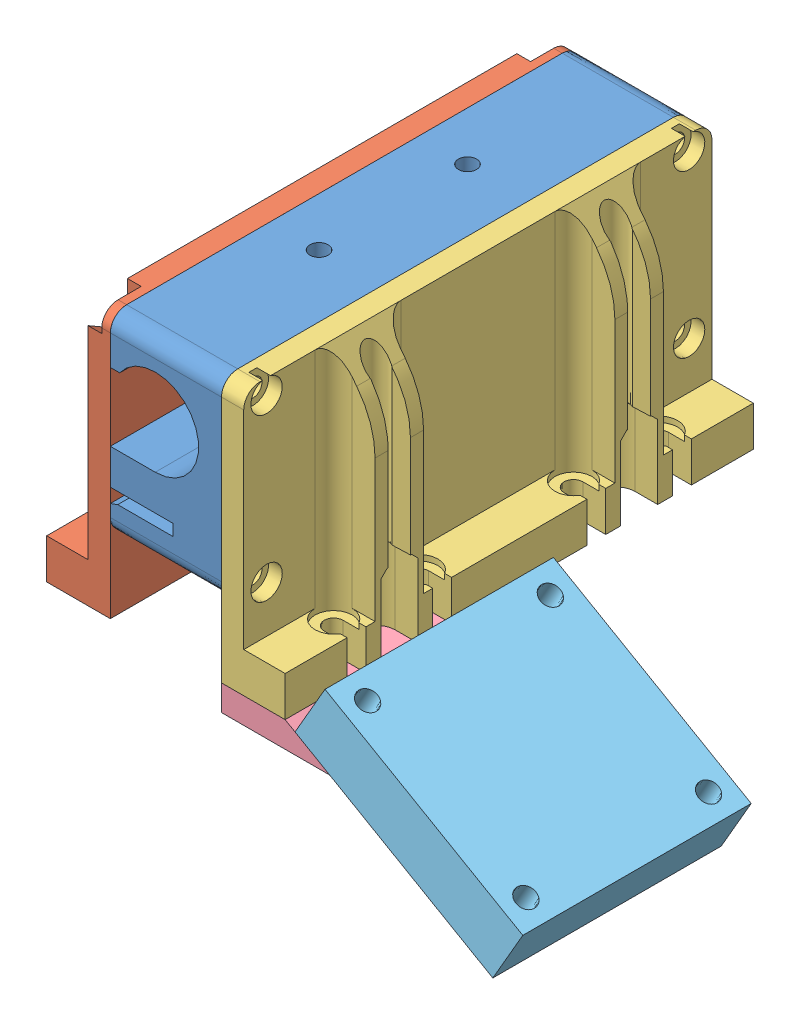
SolidWorks assembly Assem1, configuration Default. Lengths in mm.
Overall size (83.39 76.39 82).
6 component instances, 6 part files, 16 mates.
Components (placement in the parent):
- x-carriage-1: x-carriage [Default] at (14.0206 65.7443 26.0394) size (19.46 60 82)
- nozzle-mount-front-1: nozzle-mount-front [Default] at (-4.994 66.5947 108.0394) x (0 0 -1) z (1 0 0) size (82 46.39 11.15)
- nozzle-mount-rear-1: nozzle-mount-rear [Default] at (36.7706 66.5947 26.0394) x (0 0 1) z (-1 0 0) size (82 46.39 11.15)
- Part2^Assem1-1: Part2^Assem1 [Default] at (-4.994 31.9947 108.0394) x (0 0 1) z (0 -1 0) (virtual)
- Fan Holder-1: Fan Holder [Default] at (36.7706 31.9947 26.0394) x (0 0 -1) z (0 -1 0) size (40 19.86 5.84)
- Fan-1: Fan [Default] at (55.8232 20.9947 88.0394) x (0.866025 -0.5 0) z (0 0 1) size (40 10.5 40)
Mates (geometry in assembly coordinates):
- Concentric1: concentric anti-aligned: cylinder of x-carriage-1 through (25.6206 47.1943 104.0394) axis (-1 0 0) radius 1.7; circle of nozzle-mount-front-1
- Concentric2: concentric anti-aligned: cylinder of x-carriage-1 through (25.6206 47.1943 30.0394) axis (-1 0 0) radius 1.7; cylinder of nozzle-mount-front-1 through (-4.994 47.1943 30.0394) axis (1 0 0) radius 1.6
- Coincident1: coincident anti-aligned: plane of x-carriage-1 through (6.156 65.7443 26.0394) normal (-1 0 0); plane of nozzle-mount-front-1 through (6.156 75.3447 28.8894) normal (1 0 0)
- Concentric3: concentric anti-aligned: cylinder of x-carriage-1 through (25.6206 75.5343 104.0394) axis (-1 0 0) radius 1.7; cylinder of nozzle-mount-rear-1 through (27.1206 75.5343 104.0394) axis (1 0 0) radius 2.75
- Coincident2: coincident anti-aligned: plane of x-carriage-1 through (25.6206 16.1943 108.0394) normal (1 0 0); plane of nozzle-mount-rear-1 through (25.6206 75.3447 105.1894) normal (-1 0 0)
- Coincident3: coincident aligned: plane of nozzle-mount-front-1 through (6.156 78.1947 28.8894) normal (0 1 0); plane of nozzle-mount-rear-1 through (25.6206 78.1947 105.1894) normal (0 1 0)
- InPlace1: in place: plane of nozzle-mount-front-1 through (3.006 31.9947 26.0394) normal (0 -1 0); plane of ? through (0 31.9947 0) normal (0 -1 0); moOrthogonalPlaneRef_w of nozzle-mount-front-1 through (3.006 31.9947 26.0394) normal (0 -1 0); unknown of ?; plane of nozzle-mount-front-1 through (3.006 31.9947 26.0394) normal (0 -1 0); unknown of ?; plane of nozzle-mount-front-1 through (3.006 31.9947 26.0394) normal (0 -1 0); unknown of Part2^Assem1-1
- Coincident4: coincident aligned: plane of nozzle-mount-front-1; plane of Part2^Assem1-1
- Coincident5: coincident aligned: moOrthogonalPlaneRef_w of nozzle-mount-front-1 through (-4.994 31.9947 108.0394) normal (-1 0 0); plane of Part2^Assem1-1
- Coincident6: coincident anti-aligned: moOrthogonalPlaneRef_w of nozzle-mount-front-1 through (-4.994 31.9947 108.0394) normal (0 0 -1); plane of Part2^Assem1-1
- InPlace2: in place: plane of nozzle-mount-rear-1 through (28.7706 31.9947 108.0394) normal (0 -1 0); plane of ? through (0 31.9947 0) normal (0 -1 0); plane of nozzle-mount-rear-1 through (28.7706 31.9947 108.0394) normal (0 -1 0); unknown of ?; plane of nozzle-mount-rear-1 through (28.7706 31.9947 108.0394) normal (0 -1 0); line of ? through (-55 0 31.9947) axis (0 -1 0); plane of nozzle-mount-rear-1 through (28.7706 31.9947 108.0394) normal (0 -1 0); unknown of Fan Holder-1
- Coincident7: coincident aligned: plane of nozzle-mount-rear-1; plane of Fan Holder-1
- Coincident8: coincident aligned: moOrthogonalPlaneRef_w of nozzle-mount-rear-1 through (36.7706 31.9947 26.0394) normal (1 0 0); plane of Fan Holder-1
- Coincident9: coincident anti-aligned: moOrthogonalPlaneRef_w of nozzle-mount-rear-1 through (36.7706 31.9947 26.0394) normal (0 0 1); plane of Fan Holder-1
- Coincident10: coincident anti-aligned: plane of Fan Holder-1 through (36.7706 31.9947 59.0394) normal (0.5 0.866025 0); plane of Fan-1 through (55.8232 20.9947 88.0394) normal (-0.5 -0.866025 0)
- Concentric4: concentric anti-aligned: cylinder of Fan Holder-1 through (43.9668 32.4588 72.0394) axis (-0.5 -0.866025 0) radius 1.75; cylinder of Fan-1 through (41.9668 28.9947 72.0394) axis (0.5 0.866025 0) radius 1.75
